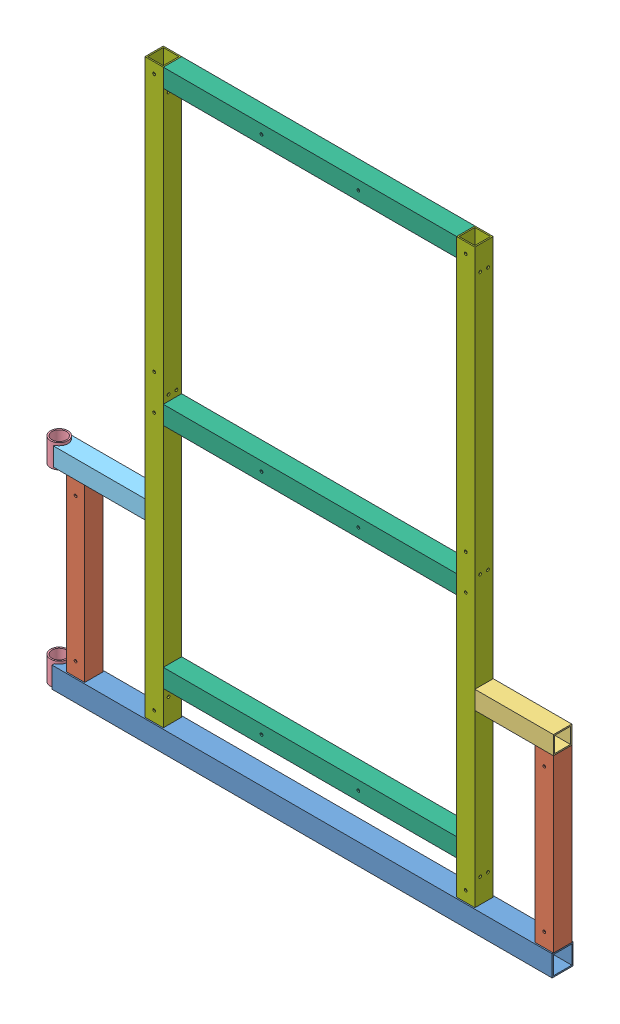
SolidWorks assembly GE-25120, configuration Default. Lengths in mm.
Overall size (1249.28 1438.27 56.99).
12 component instances, 7 part files, 35 mates.
Components (placement in the parent):
- GE-25120-01-1: GE-25120-01 [Default] at (0 25.4 0) x (-1 0 0) z (0 0 -1) size (1212.85 50.8 50.8)
- GE-25120-02-1: GE-25120-02 [Default] at (-568.325 257.9688 0) size (44.45 414.34 44.45)
- GE-25120-02-2: GE-25120-02 [Default] at (568.325 257.9688 0) size (44.45 414.34 44.45)
- GE-25120-03-2: GE-25120-03 [Default] at (495.3 487.3625 0) x (0 0 -1) z (0 -1 0) size (44.45 190.5 44.45)
- GE-25120-04-1: GE-25120-04 [Default] at (-630.2375 458.7875 0) x (-0.883932 0 -0.467616) z (0.467616 0 -0.883932) size (42.16 57.15 42.16)
- GE-25120-04-3: GE-25120-04 [Default] at (-630.2375 0 0) x (-0.883932 0 -0.467616) z (0.467616 0 -0.883932) size (42.16 57.15 42.16)
- GE-25120-07-1: GE-25120-07 [Default] at (-495.3 487.3625 0) x (0 0 -1) z (0 -1 0) size (44.45 222.25 44.45)
- GE-25120-05-1: GE-25120-05 [Default] at (0 1416.05 0) size (711.2 44.45 44.45)
- GE-25120-05-2: GE-25120-05 [Default] at (0 708.025 0) size (711.2 44.45 44.45)
- GE-25120-05-3: GE-25120-05 [Default] at (0 155.575 0) size (711.2 44.45 44.45)
- GE-25120-06-1: GE-25120-06 [Long] at (-377.825 744.5375 0) x (0 1 0) z (0 0 1) size (1387.47 44.45 44.45)
- GE-25120-06-2: GE-25120-06 [Long] at (377.825 744.5375 0) x (0 1 0) z (0 0 1) size (1387.47 44.45 44.45)
Mates (geometry in assembly coordinates):
- Coincident11: coincident aligned: plane of Shorter Height Beam-2 through (590.55 50.8 22.225) normal (1 0 0); plane of Short Beam-2 through (590.55 487.3625 0) normal (1 0 0)
- Coincident12: coincident aligned: plane of Shorter Height Beam-2 through (546.1 50.8 22.225) normal (0 0 1); plane of Short Beam-2 through (400.05 465.1375 22.225) normal (0 0 1)
- Coincident13: coincident anti-aligned: plane of Shorter Height Beam-2 through (568.325 465.1375 0) normal (0 1 0); plane of Short Beam-2 through (400.05 465.1375 22.225) normal (0 -1 0)
- Coincident36: coincident aligned: plane of Floor Beam-1 through (590.55 25.4 0) normal (1 0 0); plane of Shorter Height Beam-2 through (590.55 50.8 22.225) normal (1 0 0)
- Distance8: distance = 3.175 mm aligned: plane of Floor Beam-1 through (590.55 0 25.4) normal (0 0 1); plane of Shorter Height Beam-1 through (-590.55 50.8 22.225) normal (0 0 1)
- Coincident41: coincident anti-aligned: plane of Floor Beam-1 through (590.55 50.8 -25.4) normal (0 1 0); plane of Shorter Height Beam-1 through (-568.325 50.8 0) normal (0 -1 0)
- Coincident43: coincident anti-aligned: plane of Floor Beam-1 through (590.55 50.8 -25.4) normal (0 1 0); plane of Shorter Height Beam-2 through (568.325 50.8 0) normal (0 -1 0)
- Concentric4: concentric anti-aligned: cylinder of Floor Beam-1 through (-630.2375 0 0) axis (0 1 0) radius 21.082; cylinder of GE-24001-05-3 through (-630.2375 57.15 0) axis (0 -1 0) radius 21.082
- Coincident46: coincident aligned: plane of Floor Beam-1 through (590.55 0 -25.4) normal (0 -1 0); plane of GE-24001-05-3 through (-630.2375 0 0) normal (0 -1 0)
- Coincident48: coincident aligned: plane of Shorter Height Beam-1 through (-590.55 50.8 22.225) normal (0 0 1); plane of Short Beam Corner-1 through (-590.55 465.1375 22.225) normal (0 0 1)
- Coincident50: coincident anti-aligned: plane of Shorter Height Beam-1 through (-568.325 465.1375 0) normal (0 1 0); plane of Short Beam Corner-1 through (-590.55 465.1375 22.225) normal (0 -1 0)
- Concentric5: concentric aligned: cylinder of GE-24001-05-1 through (-630.2375 515.9375 0) axis (0 -1 0) radius 21.082; cylinder of Short Beam Corner-1 through (-630.2375 509.5875 0) axis (0 -1 0) radius 21.082
- Distance7: distance = 6.35 mm aligned: plane of GE-24001-05-1 through (-630.2375 515.9375 0) normal (0 1 0); plane of Short Beam Corner-1 through (-590.55 509.5875 22.225) normal (0 1 0)
- Distance12: distance = 685.8 mm aligned: plane of Crossbar-2 through (-355.6 685.8 22.225) normal (0 -1 0); plane of Floor Beam-1 through (590.55 0 -25.4) normal (0 -1 0)
- Distance13: distance = 82.55 mm anti-aligned: plane of Crossbar-3 through (-355.6 133.35 22.225) normal (0 -1 0); plane of Floor Beam-1 through (590.55 50.8 -25.4) normal (0 1 0)
- Coincident61: coincident anti-aligned: plane of Floor Beam-1 through (590.55 0 -25.4) normal (0 -1 0)
- Coincident62: coincident anti-aligned: plane of Floor Beam-1 through (0 25.4 0) normal (-1 0 0)
- Coincident63: coincident anti-aligned: plane of Floor Beam-1 through (0 25.4 0) normal (0 0 -1)
- Coincident64: coincident anti-aligned: plane of Floor Beam-1 through (590.55 50.8 -25.4) normal (0 1 0); plane of Tall Tube-1 through (-377.825 50.8 0) normal (0 -1 0)
- Distance14: distance = 3.175 mm aligned: plane of Tall Tube-1 through (-355.6 50.8 22.225) normal (0 0 1); plane of Floor Beam-1 through (590.55 0 25.4) normal (0 0 1)
- Coincident66: coincident anti-aligned: plane of Crossbar-3 through (-355.6 155.575 0) normal (-1 0 0); plane of Tall Tube-1 through (-355.6 50.8 22.225) normal (1 0 0)
- Coincident67: coincident anti-aligned: plane of Short Beam Corner-1 through (-400.05 487.3625 0) normal (1 0 0); plane of Tall Tube-1 through (-400.05 50.8 22.225) normal (-1 0 0)
- Parallel2: parallel aligned: cylinder of GE-24001-05-1 through (-630.2375 515.9375 0) axis (0 -1 0) radius 17.526; cylinder of GE-24001-05-3 through (-630.2375 57.15 0) axis (0 -1 0) radius 17.526
- Coincident68: coincident anti-aligned: plane of Crossbar-2 through (-355.6 708.025 0) normal (-1 0 0); plane of Tall Tube-1 through (-355.6 50.8 22.225) normal (1 0 0)
- Coincident69: coincident aligned: plane of Crossbar-2 through (-355.6 685.8 22.225) normal (0 0 1); plane of Tall Tube-1 through (-355.6 50.8 22.225) normal (0 0 1)
- Coincident70: coincident aligned: plane of Crossbar-1 through (-355.6 1393.825 22.225) normal (0 0 1); plane of Tall Tube-1 through (-355.6 50.8 22.225) normal (0 0 1)
- Coincident71: coincident anti-aligned: plane of Crossbar-1 through (-355.6 1416.05 0) normal (-1 0 0); plane of Tall Tube-1 through (-355.6 50.8 22.225) normal (1 0 0)
- Coincident72: coincident aligned: plane of Crossbar-1 through (-355.6 1438.275 22.225) normal (0 1 0); plane of Tall Tube-1 through (-377.825 1438.275 0) normal (0 1 0)
- Coincident73: coincident anti-aligned: plane of Floor Beam-1 through (590.55 50.8 -25.4) normal (0 1 0); plane of Tall Tube-2 through (377.825 50.8 0) normal (0 -1 0)
- Coincident74: coincident aligned: plane of Crossbar-3 through (-355.6 133.35 22.225) normal (0 0 1); plane of Tall Tube-2 through (400.05 50.8 22.225) normal (0 0 1)
- Coincident75: coincident anti-aligned: plane of Crossbar-3 through (355.6 155.575 0) normal (1 0 0); plane of Tall Tube-2 through (355.6 50.8 22.225) normal (-1 0 0)
- Coincident76: coincident anti-aligned: plane of Short Beam-2 through (400.05 487.3625 0) normal (-1 0 0); plane of Tall Tube-2 through (400.05 50.8 22.225) normal (1 0 0)
- Coincident77: coincident aligned: plane of Tall Tube-2 through (400.05 50.8 22.225) normal (0 0 1); plane of Shorter Height Beam-2 through (546.1 50.8 22.225) normal (0 0 1)
- Coincident78: coincident aligned: plane of Crossbar-3 through (-355.6 133.35 22.225) normal (0 0 1); plane of Tall Tube-1 through (-355.6 50.8 22.225) normal (0 0 1)
- Distance15: distance = 146.05 mm anti-aligned: plane of Shorter Height Beam-1 through (-546.1 50.8 22.225) normal (1 0 0); plane of Tall Tube-1 through (-400.05 50.8 22.225) normal (-1 0 0)
